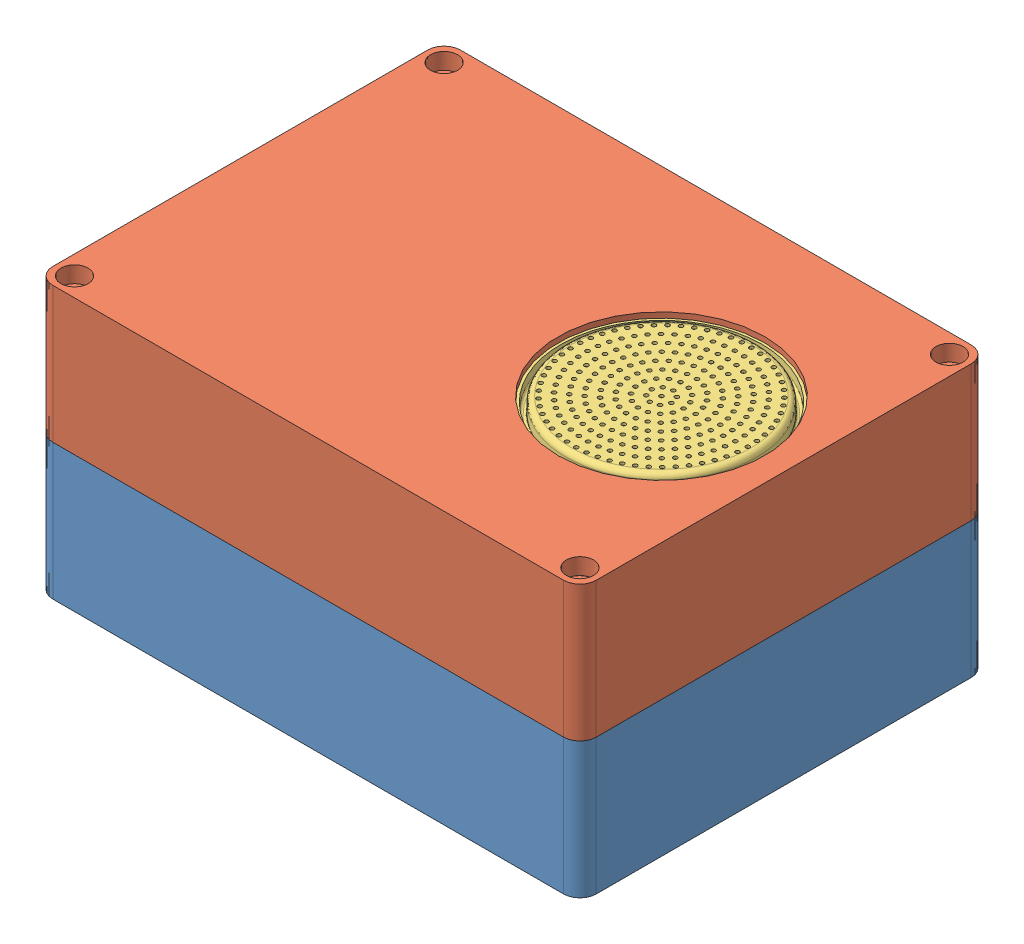
SolidWorks assembly SoilMoistureMeter, configuration Default. Lengths in mm.
Overall size (103 54.6 75).
8 component instances, 7 part files, 16 mates.
Components (placement in the parent):
- toplid-1: toplid [Default] at (33.0958 35.8969 90.0577) size (100 25 75)
- bottumlid-1: bottumlid [Default] at (43.0567 85.8969 90.0577) x (-1 0 0) z (0 0 1) size (103 25.47 75)
- rooster 1-1: rooster 1 [Default] at (85.1978 84.8969 90.3372) x (0.995892 0 0.090549) z (0 -1 0) size (38 38 3.5)
- SSD1315_OLED_Display v4.step-1: SSD1315_OLED_Display v4.step [Default] at (18.7159 40.0969 84.3754) x (0 0 1) z (0 -1 0) (suppressed, hidden)
- 1x4-keypad.stp-1: 1x4-keypad.stp [Default] at (52.5767 35.8969 84.1423) x (0 0 1) z (1 0 0) size (69 7.1 20)
- WP1513GT.stp-1: WP1513GT.stp [Default] at (-0.694 39.8969 58.0682) x (1 0 0) z (0 -1 0) size (5.45 5.9 35.6)
- WP1513IT.stp-1: WP1513IT.stp [Default] at (-0.694 39.8969 110.4693) x (1 0 0) z (0 -1 0) size (5.45 5.9 35.6)
- SSD1315_OLED_Display v4.step-2: SSD1315_OLED_Display v4.step [Default] at (17.1919 35.8969 84.3481) x (0 0 1) z (0 -1 0) size (24.8 27 11.3)
Mates (geometry in assembly coordinates):
- Concentric3: concentric anti-aligned: cylinder of bottumlid-1 through (64.7368 85.8969 83.4562) axis (0 -1 0) radius 19; cylinder of rooster 1-1 through (64.7368 82.3969 83.4562) axis (0 1 0) radius 19
- Tangent2: tangent aligned: plane of bottumlid-1 through (43.0567 85.8969 90.0577) normal (0 1 0); torus of rooster 1-1
- Coincident2: coincident anti-aligned: plane of toplid-1 through (84.6634 38.8969 118.3023) normal (0 1 0); plane of SSD1315_OLED_Display v4.step-1/SSD1315_PCB.step-1 through (18.7159 38.8969 84.3754) normal (0 -1 0)
- Parallel4: parallel aligned: line of toplid-1 through (27.0762 38.8969 96.796) axis (-1 0 0); line of SSD1315_OLED_Display v4.step-1/SSD1315_PCB.step-1 through (32.2159 40.0969 96.7754) axis (-1 0 0)
- Tangent3: tangent aligned: plane of toplid-1 through (51.8693 50.8969 76.796) normal (-1 0 0); cylinder of 1x4-keypad.stp-1 through (56.2632 39.1689 77.0923) axis (0 0 1) radius 4.3939
- Coincident6: coincident anti-aligned: plane of toplid-1 through (33.0958 35.8969 90.0577) normal (0 -1 0); plane of 1x4-keypad.stp-1 through (52.5767 35.8969 84.1423) normal (0 1 0)
- Concentric11: concentric aligned: cylinder of toplid-1 through (-0.694 50.8969 58.0682) axis (0 -1 0) radius 2.5; cone of WP1513GT.stp-1 through (-0.694 36.2469 58.0682) axis (0 -1 0)
- Coincident7: coincident anti-aligned: plane of toplid-1 through (84.6634 38.8969 118.3023) normal (0 1 0); plane of WP1513GT.stp-1 through (-0.694 38.8969 58.0682) normal (0 -1 0)
- Concentric12: concentric aligned: cylinder of toplid-1 through (-0.694 50.8969 110.4693) axis (0 -1 0) radius 2.5; cone of WP1513IT.stp-1 through (-0.694 36.2469 110.4693) axis (0 -1 0)
- Coincident8: coincident anti-aligned: plane of toplid-1 through (84.6634 38.8969 118.3023) normal (0 1 0); plane of WP1513IT.stp-1 through (-0.694 38.8969 110.4693) normal (0 -1 0)
- Coincident10: coincident anti-aligned: plane of toplid-1 through (33.0958 60.8969 90.0577) normal (0 1 0); plane of bottumlid-1 through (43.0567 60.8969 90.0577) normal (0 -1 0)
- Coincident12: coincident anti-aligned: line of toplid-1 through (-8.9238 60.8969 121.796) axis (1 0 0); line of bottumlid-1 through (85.0762 60.8969 121.796) axis (-1 0 0)
- Parallel6: parallel anti-aligned: plane of toplid-1 through (33.0958 60.8969 90.0577) normal (0 1 0); plane of bottumlid-1 through (43.0567 60.8969 90.0577) normal (0 -1 0)
- Coincident14: coincident anti-aligned: line of toplid-1 through (-11.9238 60.8969 49.796) axis (0 0 1); line of bottumlid-1 through (-11.9238 60.8969 118.796) axis (0 0 -1)
- Coincident15: coincident anti-aligned: plane of toplid-1 through (33.0958 35.8969 90.0577) normal (0 -1 0); plane of SSD1315_OLED_Display v4.step-2 through (17.1919 35.8969 84.3481) normal (0 1 0)
- Parallel7: parallel anti-aligned: line of toplid-1 through (-11.9238 35.8969 49.796) axis (0 0 1); line of SSD1315_OLED_Display v4.step-2 through (3.6919 34.6969 96.7481) axis (0 0 -1)
